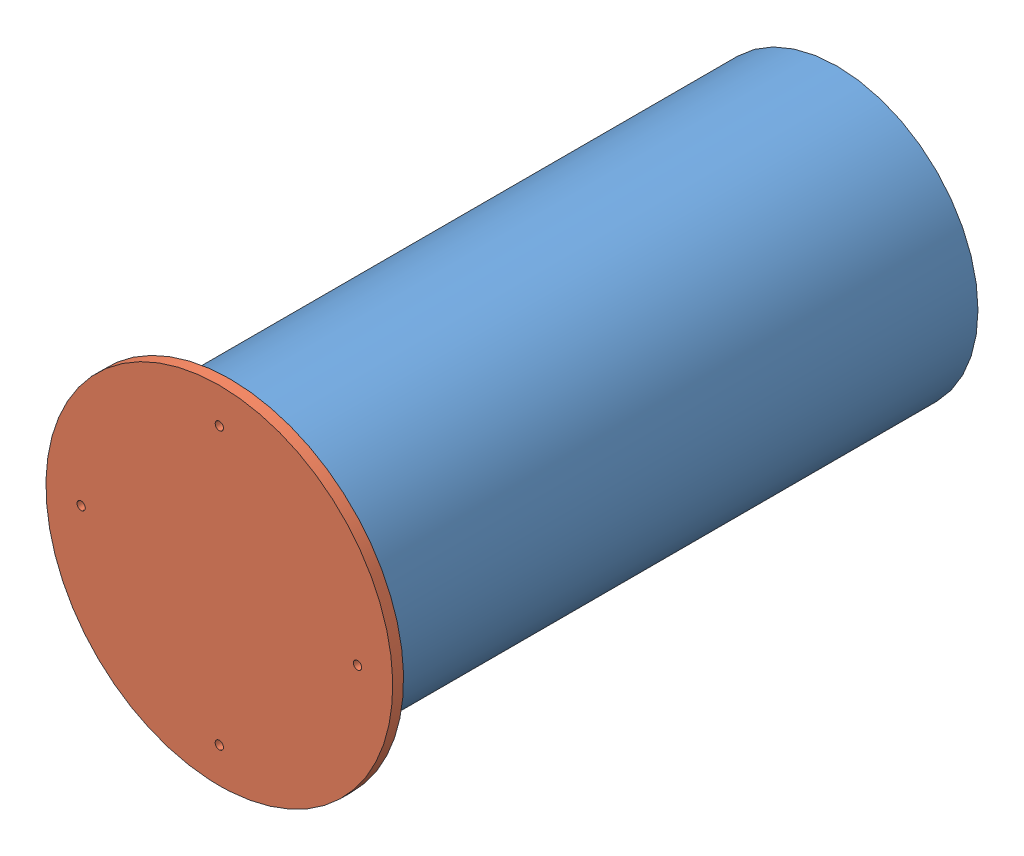
SolidWorks assembly Battery Pod, configuration Default. Lengths in mm.
Overall size (101.6 101.6 180.97).
6 component instances, 5 part files, 5 mates.
Components (placement in the parent):
- Battery Pod Tube-1: Battery Pod Tube [Default] at (-12.1841 151.484 -90.0307) size (82.55 82.55 177.8)
- Battery Pod Front Lid-1: Battery Pod Front Lid [Default] at (-12.1841 151.484 87.7693) x (1 0 0) z (0 -1 0) size (101.6 12.7 101.6)
- Battery Holder-1: Battery Holder [Default] at (44.3997 121.2811 -4.0894) size (52.45 60.64 142.88)
  - Battery Holder-1: Battery Holder [Default] at (-82.8093 -0.1184 78.8907) size (52.45 60.64 142.88)
  - Battery-1: Battery [Default] at (-56.5838 1.4691 8.7232) x (0 0 -1) z (1 0 0) size (135.89 55.88 42.93)
- Battery Board-1: Battery Board [Default] at (-12.1841 151.484 72.5787) size (76.2 76.2 2.54)
Mates (geometry in assembly coordinates):
- Coincident1: coincident anti-aligned: plane of Battery Pod Tube-1 through (-12.1841 151.484 87.7693) normal (0 0 1); plane of Battery Pod Front Lid-1 through (-12.1841 151.484 87.7693) normal (0 0 -1)
- Concentric2: concentric aligned: circle of Battery Pod Tube-1; circle of Battery Pod Front Lid-1
- Concentric3: concentric anti-aligned: circle of Battery Pod Tube-1; circle of Battery Holder-1/Battery Holder-1
- Concentric4: concentric aligned: cylinder of Battery Pod Tube-1 through (-12.1841 151.484 87.7693) axis (0 0 -1) radius 38.1; cylinder of Battery Board-1 through (-12.1841 151.484 75.1187) axis (0 0 -1) radius 38.1
- Coincident2: coincident anti-aligned: plane of Battery Holder-1/Battery-1 through (-33.6471 178.6303 72.5787) normal (0 0 1); plane of Battery Board-1 through (-12.1841 151.484 72.5787) normal (0 0 -1)
